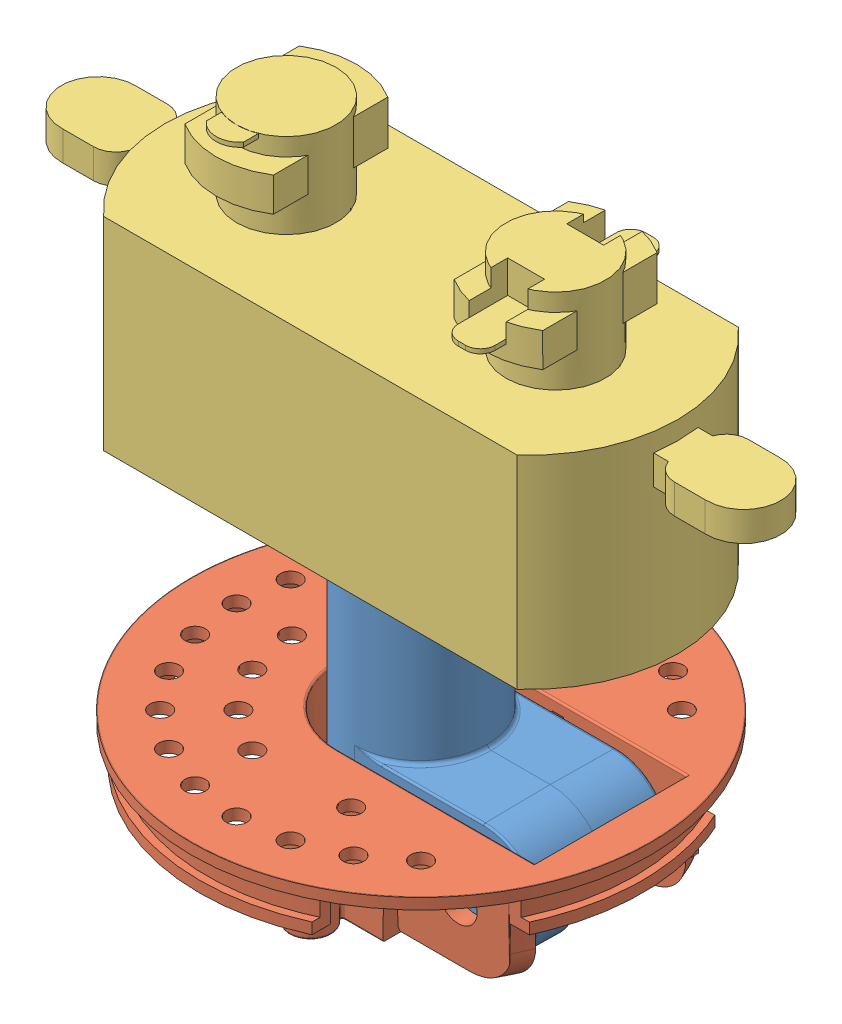
SolidWorks assembly VIL-1506-底座, configuration 默认. Lengths in mm.
Overall size (97.5 80.43 62.2).
4 component instances, 3 part files, 0 mates.
Components (placement in the parent):
- VILLY-15W支臂组合-1: VILLY-15W支臂组合 [默认] at (25.0006 128.0006 0) x (-1 -0.000082 0) z (0 0 1) size (62.2 51.51 62.2)
  - 7______-1: 7______ [默认] at (0 0 9) x (1 0 0) z (0 0 -1) size (34.04 49.12 19.05)
  - VILLY-1-1: VILLY-1 [默认] at (24.9999 -8.5014 0) x (0 0 1) z (1 -0.000082 0) size (62.2 17.5 62.2)
- 金芭迪3线导轨头-1: 金芭迪3线导轨头 [默认] at (-0.0026 166.9186 0) x (1 0.000082 0) z (0 0 1) size (97.5 41 30)
